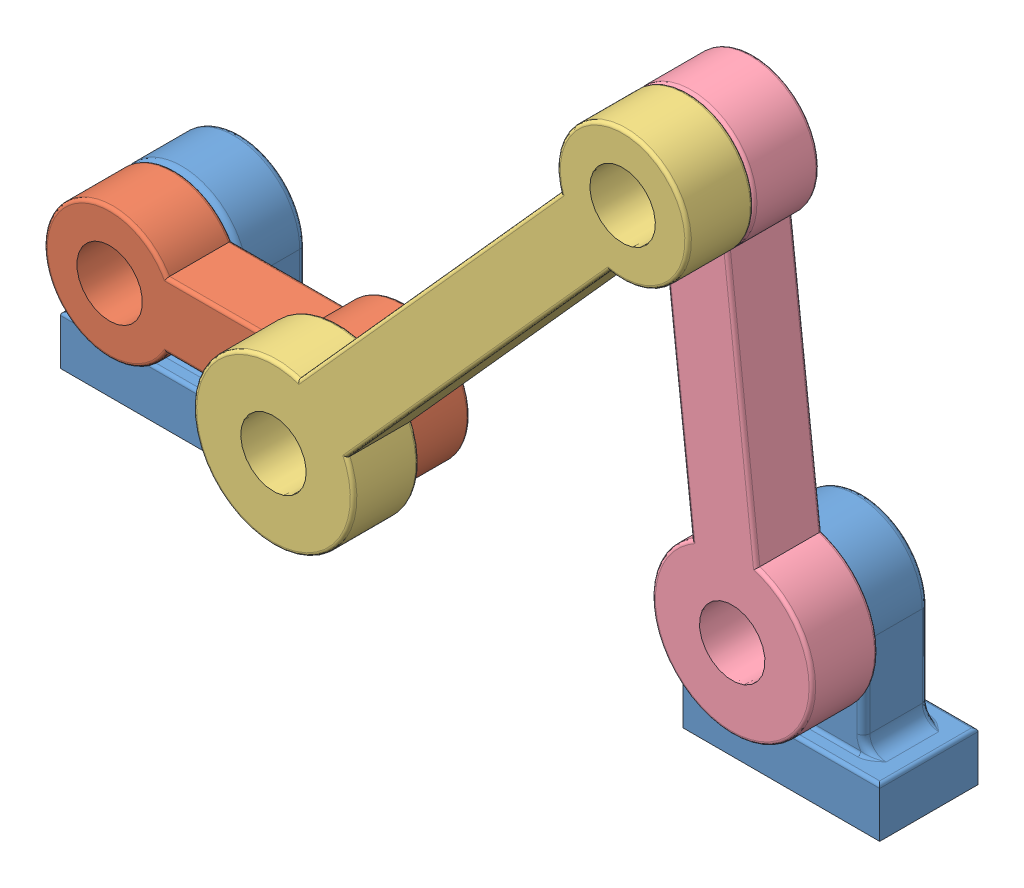
SolidWorks assembly 4_bar_assembly, configuration Default. Lengths in mm.
Overall size (250 195.1 65).
5 component instances, 4 part files, 13 mates.
Components (placement in the parent):
- bearing-2: bearing [Défaut] at (0 15 0) x (1 0 0) z (0 -1 0) size (60 30 65)
- crank-2: crank [Défaut] at (100 45 -5) x (0 -1 0) z (0 0 1) size (40 110 20)
- extension-2: extension [Défaut] at (206.547 163.8823 15) x (0.744685 -0.667416 0) z (0 0 1) size (48.92 204.1 20)
- rocker-2: rocker [Défaut] at (206.547 163.8823 -5) x (0.993658 0.112445 0) z (0 0 1) size (48.92 164.1 20)
- bearing-3: bearing [Défaut] at (190 15 0) x (1 0 0) z (0 -1 0) size (60 30 65)
Mates (geometry in assembly coordinates):
- Coincident2: coincident: plane of bearing-2 through (0 0 0) normal (0 -1 0); plane of assembly through (0 0 0) normal (0 1 0)
- Coincident3: coincident: plane of bearing-2 through (0 0 -30) normal (-1 0 0); plane of assembly through (0 0 0) normal (1 0 0)
- Coincident5: coincident: plane of bearing-2 through (0 0 0) normal (0 0 1); plane of assembly through (0 0 0) normal (0 0 1)
- Coincident7: coincident: plane of bearing-3 through (190 0 0) normal (0 0 1); plane of assembly through (0 0 0) normal (0 0 1)
- Coincident8: coincident: plane of bearing-3 through (190 0 0) normal (0 -1 0); plane of assembly through (0 0 0) normal (0 1 0)
- Distance2: distance = 130 mm: plane of bearing-2 through (60 0 0) normal (1 0 0); plane of bearing-3 through (190 0 -30) normal (-1 0 0)
- Hinge1: hinge: cylinder of crank-2 through (30 45 15) axis (0 0 -1) radius 10; cylinder of bearing-2 through (30 45 -5) axis (0 0 -1) radius 10; plane of bearing-2 through (30 45 -5) normal (0 0 1); plane of crank-2 through (100 45 -5) normal (0 0 -1)
- Hinge3: hinge: cylinder of extension-2 through (100 45 35) axis (0 0 -1) radius 10; cylinder of crank-2 through (100 45 15) axis (0 0 -1) radius 10; plane of extension-2 through (206.547 163.8823 15) normal (0 0 -1); plane of crank-2 through (100 45 15) normal (0 0 1)
- Concentric7: concentric: cylinder of extension-2 through (206.547 163.8823 35) axis (0 0 -1) radius 10; cylinder of rocker-2 through (206.547 163.8823 15) axis (0 0 -1) radius 10
- Concentric4: concentric: cylinder of rocker-2 through (220 45 15) axis (0 0 -1) radius 10; cylinder of bearing-3 through (220 45 -5) axis (0 0 -1) radius 10
- Hinge5: hinge: cylinder of rocker-2 through (220 45 15) axis (0 0 -1) radius 10; cylinder of bearing-3 through (220 45 -5) axis (0 0 -1) radius 10; plane of rocker-2 through (183.4777 158.9302 -5) normal (0 0 -1); plane of bearing-3 through (220 45 -5) normal (0 0 1)
- Coincident14: coincident: point of rocker-2; point of bearing-3
- Parallel2: parallel: plane of crank-2 through (82.6795 35 15) normal (0 -1 0); plane of assembly through (0 0 0) normal (0 1 0)
